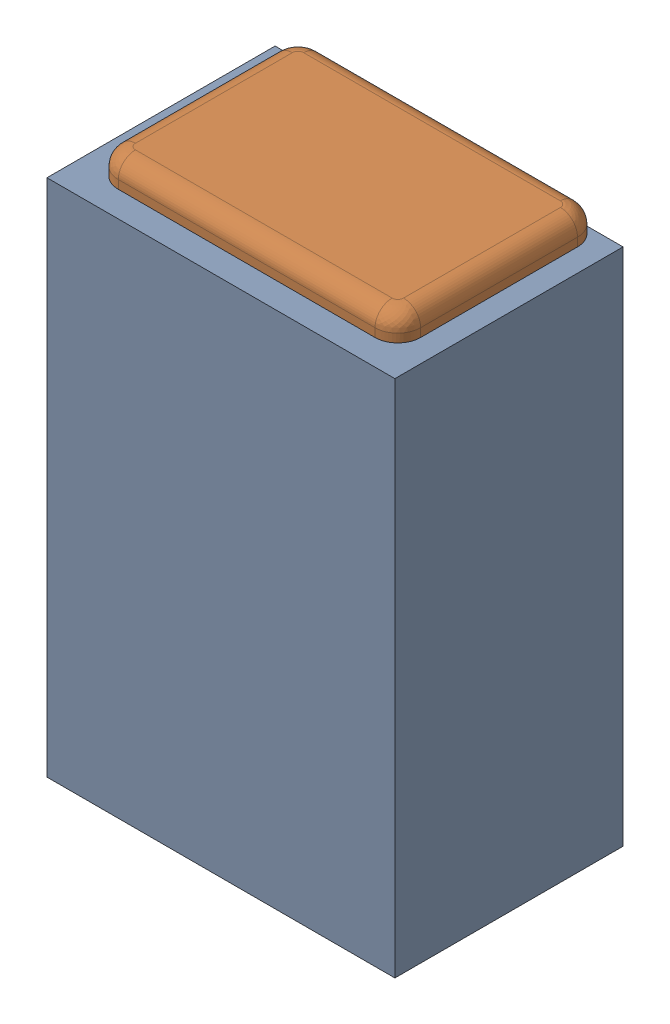
SolidWorks assembly C8, configuration Default. Lengths in mm.
Overall size (0.61 1 0.4).
3 component instances, 2 part files, 0 mates.
Components (placement in the parent):
- 1088881848-1: 1088881848 [Default] at (8.05 38.45 0) size (0.61 0.91 0.4)
  - Extruded-1-1: Extruded-1 [Default] at origin size (0.61 0.91 0.4)
- C0402-1: C0402 [Default] at (8.0501 38.4499 0) x (0 -1 0) z (-1 0 0) size (1 0.36 0.54)
